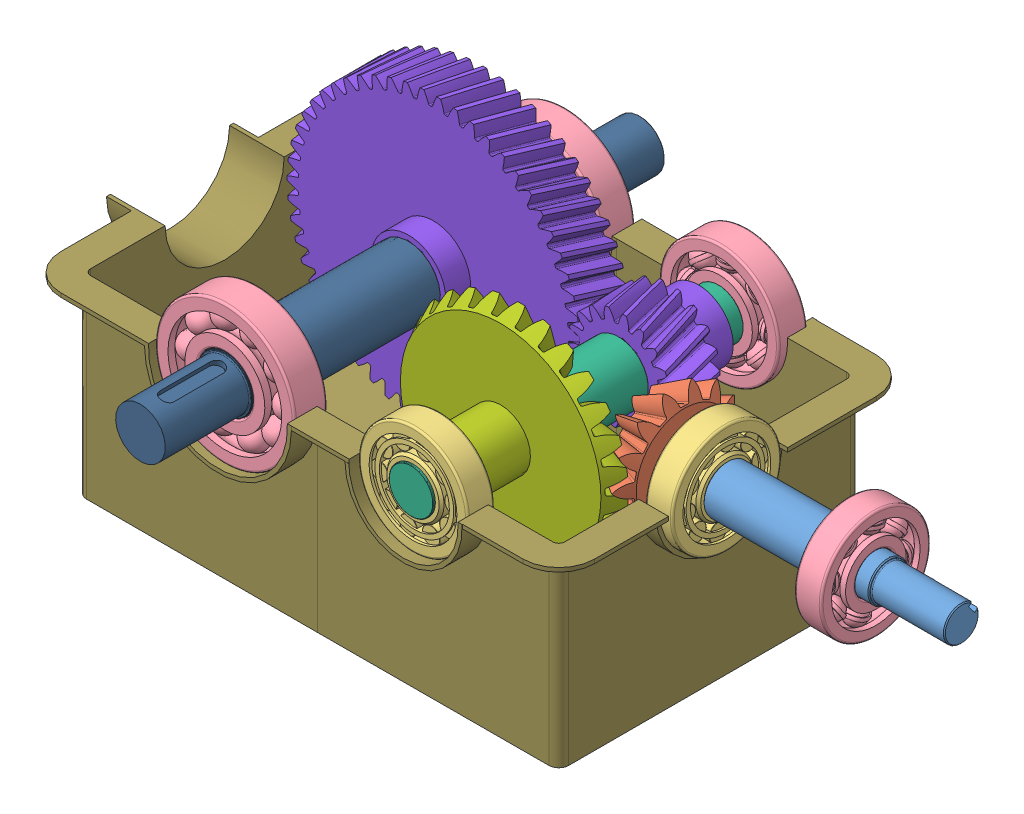
SolidWorks assembly gearbox, configuration Default. Lengths in mm.
Overall size (799.53 363.61 503).
22 component instances, 12 part files, 8 mates.
Components (placement in the parent):
- Assem1-1: Assem1 [Default] at (116.7687 -27.2467 -34.4144) size (323.99 180.58 179.96)
  - shaft1-1: shaft1 [Default] at (31.4367 201.9791 261.441) x (1 0 0) z (0 0.796608 0.604496) size (318.5 48 48)
  - straight bevel pinion_am-1: straight bevel pinion_am [Metric - Straight bevel pinion 8M14PT 27GT 20PA 41.5FW ---14O45H40MD40R1] at (-79.3839 201.9791 261.441) x (-1 0 0) z (0 -0.796608 -0.604496) size (44.71 127.04 130.28)
  - radial cylindrical roller bearing_skf-1: radial cylindrical roller bearing_skf [SKF - NU 408 - 10,DE,AC,10] at (-50.0633 201.9791 261.441) x (1 0 0) z (0 -0.464071 0.885798) size (27 110 110)
  - radial ball bearing_68_skf-2: radial ball bearing_68_skf [SKF - 6408 - 8,DE,AC,8_68] at (99.9367 201.9791 261.441) x (1 0 0) z (0 0.184049 0.982917) size (27 110 110)
  - bush1-1: bush1 [Default] at (-63.5633 201.9791 261.441) x (0 0 1) z (-1 0 0) size (48 48 15.8)
- Assem2-1: Assem2 [Default] at (108.8839 441.1216 115.03) x (0 0 1) z (0 -1 0) size (339 286.94 286.73)
  - shaft2-1: shaft2 [Default] at (121.8135 193.7516 287.3385) x (1 0 0) z (0 0.931077 -0.364824) size (339 60 60)
  - straight bevel gear_am-1: straight bevel gear_am [Metric - Straight bevel gear 8M 27GT 14PT 20PA 41.5FW ---27O60H121MD45R1] at (182.9357 185.543 266.3893) x (-1 0 0) z (0 -0.931077 0.364824) size (88.99 221.15 221.53)
  - helical gear_3_am-1: helical gear_3_am [Metric - LH Helical gear 5M 18T 15HA 20PA 50FW ---18O70H80L50.0R1] at (13.7159 185.543 266.3893) x (1 0 0) z (0 0.931077 -0.364824) size (80 103.26 103.26)
  - heavy duty external retaining ring_am-2: heavy duty external retaining ring_am [B27.8M - 3DM1-50] at (234.4024 185.543 266.3893) x (0 0.839381 -0.543544) z (-1 0 0) size (57.8 62.09 3.2)
  - radial ball bearing_68_skf-1: radial ball bearing_68_skf [SKF - 6409 - 8,DE,AC,10_68] at (-51.2841 185.543 266.3893) x (1 0 0) z (0 -0.999998 -0.002032) size (29 120 120)
  - heavy duty external retaining ring_am-3: heavy duty external retaining ring_am [B27.8M - 3DM1-50] at (-19.4841 185.543 266.3893) x (0 0.887875 0.460084) z (-1 0 0) size (57.8 62.09 3.2)
  - radial cylindrical roller bearing_skf-1: radial cylindrical roller bearing_skf [SKF - NU 408 - 10,DE,AC,15] at (257.7159 185.543 266.3893) x (1 0 0) z (0 0.91747 0.397806) size (27 110 110)
- Assem3-1: Assem3 [Default] at (-520.9781 -217.2515 39.1314) x (0 0 1) z (0 1 0) size (503 349.2 349.22)
  - shaft3-1: shaft3 [Default] at (45.3704 257.3941 391.9838) x (1 0 0) z (0 -0.978527 0.206121) size (503 65 65)
  - helical gear_3_am-1: helical gear_3_am [Metric - RH Helical gear 5M 55T 15HA 20PA 50FW ---55O75H75L55.0R1] at (139.6623 257.3941 391.9838) x (-1 0 0) z (0 0.978527 -0.206121) size (75 294.79 294.77)
  - radial ball bearing_68_skf-1: radial ball bearing_68_skf [SKF - 6411 - 10,DE,AC,10_68] at (23.1623 257.3941 391.9838) x (1 0 0) z (0 -0.047 0.998895) size (33 140 140)
  - radial ball bearing_68_skf-2: radial ball bearing_68_skf [SKF - 6411 - 10,DE,NC,10_68] at (333.1623 257.3941 391.9838) x (1 0 0) z (0 0.028368 0.999598) size (33 140 140)
  - bush3-1: bush3 [Default] at (39.6623 257.3941 391.9838) x (0 0 -1) z (1 0 0) size (63 63 50)
- Box-1: Box [Default] at (-129.1013 -14.2677 224.773) x (-1 0 0) z (0 1 0) size (562 357 257)
- Box-2: Box [Default] at (-129.1013 371.7323 212.162) x (-1 0 0) z (0 -1 0) size (562 357 257) (hidden)
Mates (geometry in assembly coordinates):
- Parallel1: parallel anti-aligned: plane of Assem1-1 through (116.7687 -27.2467 -34.4144) normal (1 0 0); plane of Assem2-1 through (108.8839 441.1216 115.03) normal (-1 0 0)
- Coincident6: coincident anti-aligned: plane of Assem1-1 through (116.7687 174.7323 -34.4144) normal (0 1 0); plane of Assem2-1 through (108.8839 174.7323 115.03) normal (0 -1 0)
- Coincident7: coincident anti-aligned: plane of Assem2-1 through (108.8839 174.7323 115.03) normal (0 -1 0); plane of Assem3-1 through (-520.9781 174.7323 39.1314) normal (0 1 0)
- Parallel3: parallel anti-aligned: plane of Box-1 through (-129.1013 -14.2677 224.773) normal (0 -1 0)
- Parallel4: parallel anti-aligned: plane of Box-1 through (-129.1013 178.7323 64.773) normal (0 0 -1)
- Concentric3: concentric anti-aligned: cylinder of Assem3-1/radial ball bearing_68_skf-1 through (-263.5841 174.7323 41.6562) axis (0 0 1) radius 70; cylinder of Box-1 through (-263.5841 174.7323 395.773) axis (0 0 -1) radius 70
- Coincident8: coincident anti-aligned: plane of Box-1 through (-129.1013 178.7323 224.773) normal (0 1 0); plane of Box-2 through (-129.1013 178.7323 212.162) normal (0 -1 0)
- Coincident11: coincident aligned: plane of Box-1 through (53.175 178.7323 224.773) normal (1 0 0); plane of Box-2 through (53.175 178.7323 212.162) normal (1 0 0)
